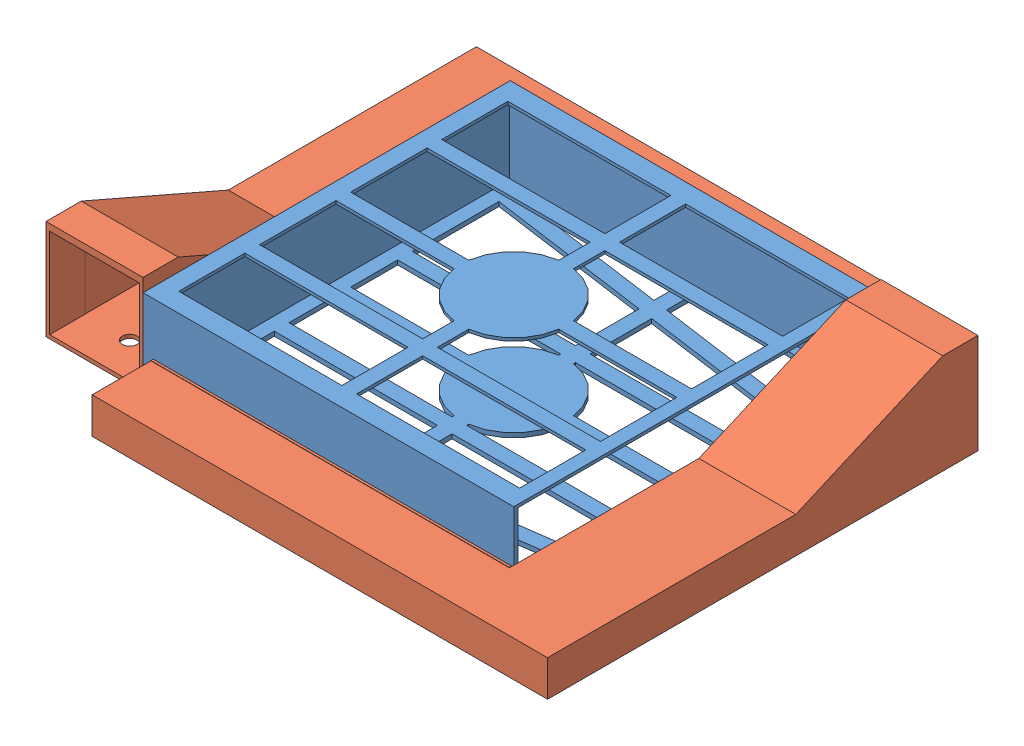
SolidWorks assembly Assembly_1, configuration Default. Lengths in mm.
Overall size (192.2 34 168).
3 component instances, 2 part files, 6 mates.
Components (placement in the parent):
- Fan housing_3-1: Fan housing_3 [Default] at (59.3407 9.5892 -3.0024) size (126.2 29.5 125)
- Air curtain_1-1: Air curtain_1 [Default] at (-83.3593 9.0892 59.4976) size (155 34 146.5)
- Air curtain_1-2: Air curtain_1 [Default] at (75.8407 9.0892 -65.5024) x (-1 0 0) z (0 0 -1) size (155 34 146.5)
Mates (geometry in assembly coordinates):
- Coincident1: coincident anti-aligned: plane of Fan housing_3-1 through (-66.8593 26.5892 -65.5024) normal (-1 0 0); plane of Air curtain_1-1 through (-66.8593 25.5892 47.4976) normal (1 0 0)
- Coincident2: coincident aligned: plane of Fan housing_3-1 through (-105.6593 -7.4108 59.4976) normal (0 -1 0); plane of Air curtain_1-1 through (-99.8593 -7.4108 47.4976) normal (0 -1 0)
- Coincident3: coincident aligned: plane of Fan housing_3-1 through (-105.6593 26.5892 59.4976) normal (0 0 1); plane of Air curtain_1-1 through (-83.3593 9.0892 59.4976) normal (0 0 1)
- Coincident4: coincident aligned: plane of Fan housing_3-1 through (-105.6593 -7.4108 59.4976) normal (0 -1 0); plane of Air curtain_1-2 through (92.3407 -7.4108 -53.5024) normal (0 -1 0)
- Coincident5: coincident aligned: plane of Fan housing_3-1 through (-105.6593 26.5892 -65.5024) normal (0 0 -1); plane of Air curtain_1-2 through (75.8407 9.0892 -65.5024) normal (0 0 -1)
- Coincident6: coincident anti-aligned: plane of Fan housing_3-1 through (59.3407 9.5892 -3.0024) normal (1 0 0); plane of Air curtain_1-2 through (59.3407 25.5892 -53.5024) normal (-1 0 0)
